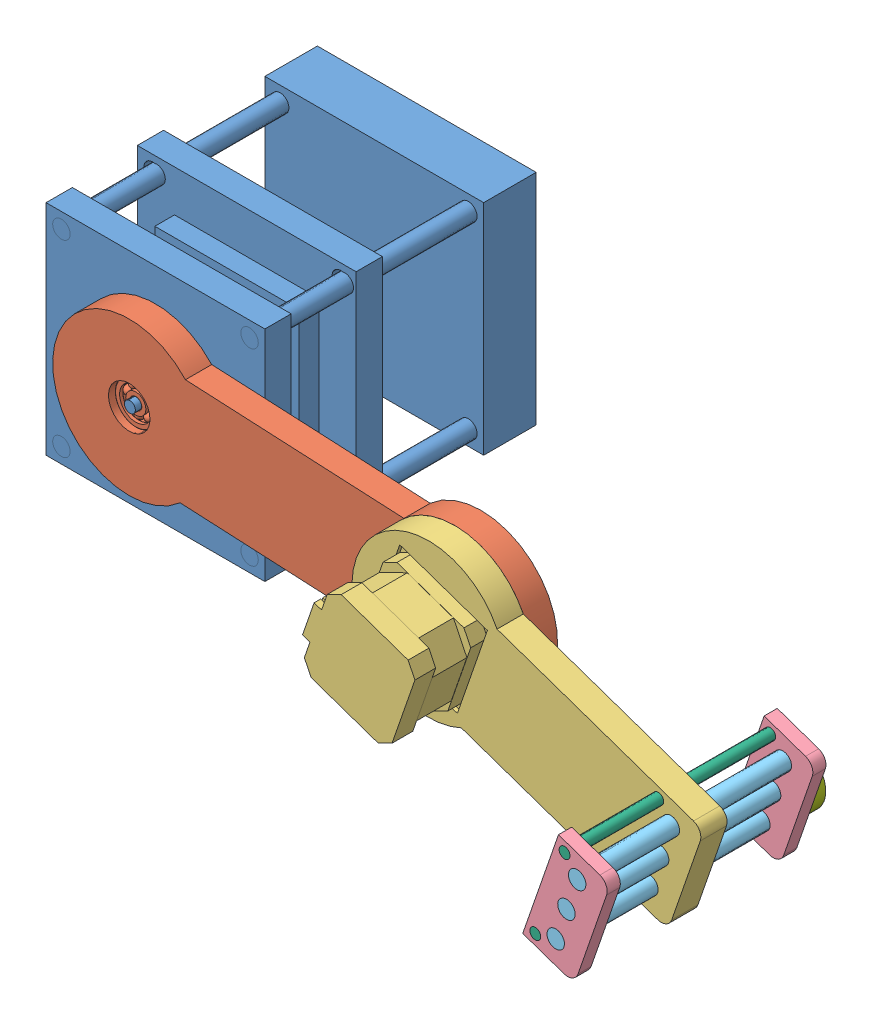
SolidWorks assembly Ensamblaje_Scara, configuration Predeterminado. Lengths in mm.
Overall size (329.7 131.14 272.67).
12 component instances, 7 part files, 9 mates.
Components (placement in the parent):
- Pieza_Base-1: Pieza_Base [Predeterminado] at (-8.1115 -2.934 67.85) size (101.8 100 135.7)
- Pieza_Link1-2: Pieza_Link1 [Predeterminado] at (-8.1115 -2.934 191.85) x (0.998774 -0.049511 0) z (0 0 1) size (218.99 70 12)
- Pieza_Link2-2: Pieza_Link2 [Predeterminado] at (246.5427 -46.9063 203.85) x (0.945107 -0.326762 0) z (0 0 1) size (159.49 70 55.2)
- Ensamblaje_Link3-1: Ensamblaje_Link3 [Predeterminado] at (246.5427 -46.9063 252.6696) x (0.945107 -0.326762 0) z (0 0 1) size (25 50 100)
  - Pieza1-1: Pieza1 [Predeterminado] x (0 1 0) z (1 0 0) size (50 6 25)
  - Pieza5-1: Pieza5 [Predeterminado] at (0 -15 6) x (0 1 0) z (-1 0 0) size (8 100 8)
  - Pieza5-2: Pieza5 [Predeterminado] at (0 15 -94) x (1 0 0) z (0 -1 0) size (8 100 8)
  - Pieza9-1: Pieza9 [Predeterminado] at (-8 -20.5 6) x (1 0 0) z (0 1 0) size (5 100 5)
  - Pieza9-2: Pieza9 [Predeterminado] at (-8 20.5 6) x (1 0 0) z (0 1 0) size (5 100 5)
  - Pieza1-2: Pieza1 [Predeterminado] at (0 0 -94) x (0 1 0) z (1 0 0) size (50 6 25)
  - Pieza5-3: Pieza5 [Predeterminado] at (0 0 6) x (1 0 0) z (0 1 0) size (8 100 8)
- Griper-1: Griper [Predeterminado] at (246.5427 -46.9063 158.6696) x (0.041467 -0.99914 0) z (0.99914 0.041467 0) size (25 6 25)
Mates (geometry in assembly coordinates):
- Concéntrica4: concentric aligned: cylinder of Pieza_Base-1 through (-8.1115 -2.934 203.55) axis (0 0 -1) radius 2.5; cylinder of Pieza_Link1-2 through (-8.1115 -2.934 218.4875) axis (0 0 -1) radius 2.5
- Concéntrica5: concentric anti-aligned: cylinder of Pieza_Link1-2 through (140.6956 -10.3106 218.4875) axis (0 0 -1) radius 2.5; cylinder of Pieza_Link2-2 through (140.6956 -10.3106 192.15) axis (0 0 1) radius 2.5
- Concéntrica6: concentric anti-aligned: cylinder of Pieza_Link2-2 through (241.6412 -61.0829 215.85) axis (0 0 -1) radius 4; cylinder of Ensamblaje_Link3-1/Pieza5-1 through (241.6412 -61.0829 158.6696) axis (0 0 1) radius 4
- Concéntrica7: concentric aligned: cylinder of Pieza_Link2-2 through (251.4441 -32.7297 215.85) axis (0 0 -1) radius 4; cylinder of Ensamblaje_Link3-1/Pieza5-2 through (251.4441 -32.7297 258.6696) axis (0 0 -1) radius 4
- Distancia límite2: limit distance = 36.8196 mm anti-aligned: plane of Pieza_Link2-2 through (140.6956 -10.3106 215.85) normal (0 0 1); plane of Ensamblaje_Link3-1/Pieza1-1 through (246.5427 -46.9063 252.6696) normal (0 0 -1)
- Coincidente4: coincident anti-aligned: plane of Pieza_Base-1 through (-8.1115 -2.934 191.85) normal (0 0 1); plane of Pieza_Link1-2 through (-8.1115 -2.934 191.85) normal (0 0 -1)
- Coincidente5: coincident anti-aligned: plane of Pieza_Link1-2 through (-8.1115 -2.934 203.85) normal (0 0 1); plane of Pieza_Link2-2 through (140.6956 -10.3106 203.85) normal (0 0 -1)
- Concéntrica8: concentric aligned: cylinder of Ensamblaje_Link3-1/Pieza5-3 through (246.5427 -46.9063 158.6696) axis (0 0 1) radius 4; cylinder of Griper-1 through (246.5427 -46.9063 152.6696) axis (0 0 1) radius 12.5
- Coincidente8: coincident anti-aligned: plane of Ensamblaje_Link3-1/Pieza1-2 through (246.5427 -46.9063 158.6696) normal (0 0 -1); plane of Griper-1 through (246.5427 -46.9063 158.6696) normal (0 0 1)
